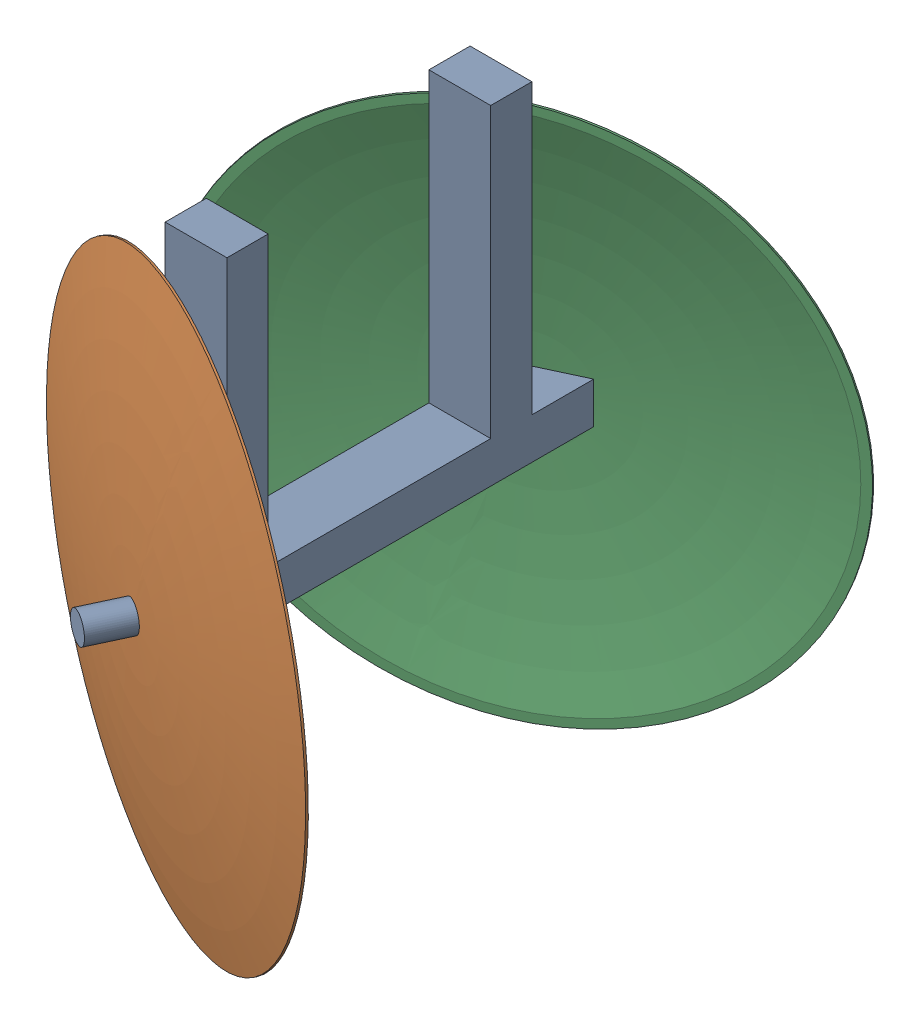
SolidWorks assembly mud cover, configuration Default. Lengths in mm.
Overall size (388.31 418.41 424.12).
3 component instances, 2 part files, 2 mates.
Components (placement in the parent):
- plough frame-1: plough frame [Default] at (54.6506 111.3859 74.7788) size (47.33 203.2 301.25)
- plough closer-1: plough closer [Default<As Machined>] at (73.341 124.0859 179.0615) x (0.289634 0.947561 0.135059) z (-0.422618 0 0.906308) size (330.2 330.2 21.53)
- plough closer-4: plough closer [Default<As Machined>] at (73.341 124.0859 -29.2015) x (-0.289634 -0.947561 0.135059) z (-0.422618 0 -0.906308) size (330.2 330.2 21.53)
Mates (geometry in assembly coordinates):
- Coincident1: coincident anti-aligned: line of plough frame-1 through (53.4822 124.0859 221.6489) axis (0.422618 0 -0.906308); line of plough closer-1 through (108.0302 124.0859 104.6704) axis (-0.422618 0 0.906308)
- Distance1: distance = 25.4 mm aligned: plane of plough frame-1 through (53.4822 124.0859 221.6489) normal (-0.422618 0 0.906308); sphere of plough closer-1
